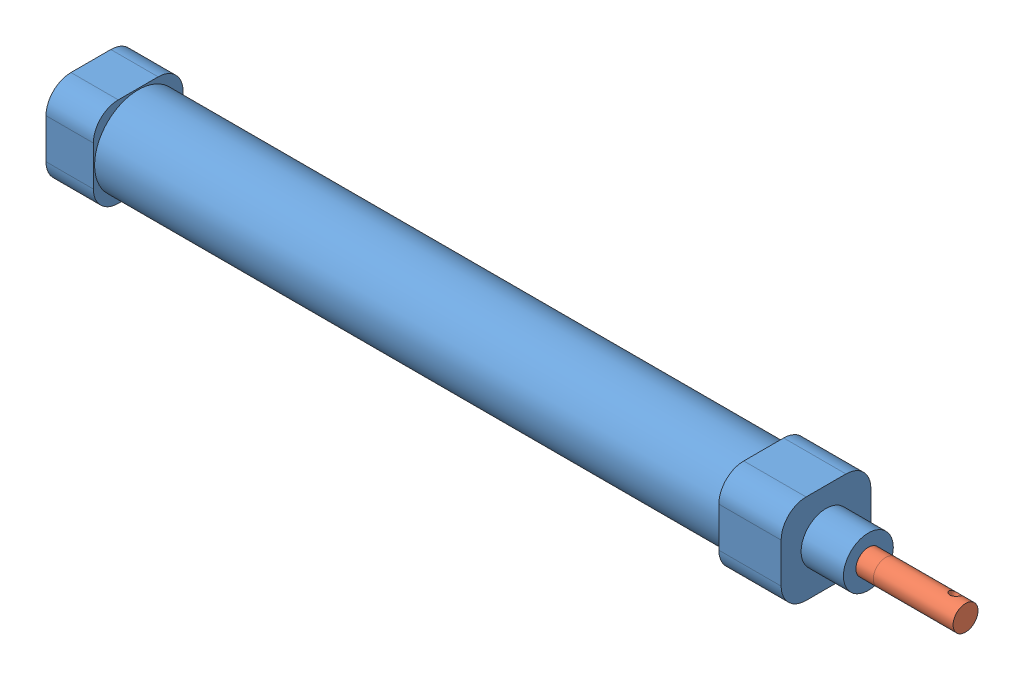
SolidWorks assembly 推环装置（单）, configuration 默认. Lengths in mm.
Overall size (175.5 18 18).
3 component instances, 2 part files, 0 mates.
Components (placement in the parent):
- 16x100标准型-1: 16x100标准型 [默认] at (-234.5005 -21.5583 173.7409) x (0 0 -1) z (1 0 0) size (18 18 175.5)
  - 16x100标准型壳-1: 16x100标准型壳 [默认] at (-1.7591 0.557 78) size (18 18 156)
  - 16x100标准型轴-1: 16x100标准型轴 [默认] at (-1.7591 0.557 87.5) x (0.935449 -0.353463 0) z (0 0 1) size (5 5 166)
